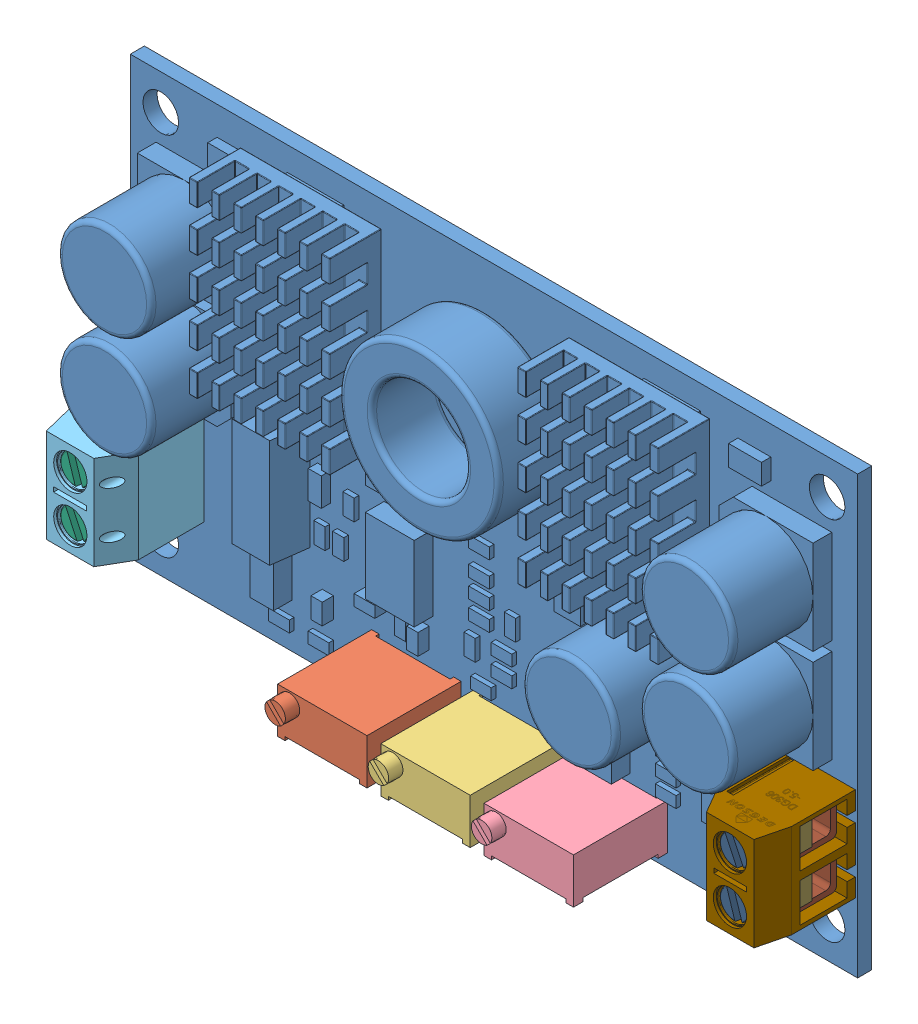
SolidWorks assembly LTC 3780 Mudule v11, configuration Predeterminado. Lengths in mm.
Overall size (77.5 46.5 15.68).
20 component instances, 12 part files, 0 mates.
Components (placement in the parent):
- LTC 3780 Mudule-1: LTC 3780 Mudule [Predeterminado] at origin size (77.5 46.5 14)
- Trimpot_3296W v1-1: Trimpot_3296W v1 [Predeterminado] at (-8.265 -19.415 0) x (-1 0 0) z (0 0 1) size (9.53 4.83 14.15)
- Trimpot_3296W v1 (1)-1: Trimpot_3296W v1 (1) [Predeterminado] at (2.735 -19.415 0) x (-1 0 0) z (0 0 1) size (9.53 4.83 14.15)
- Trimpot_3296W v1 (2)-1: Trimpot_3296W v1 (2) [Predeterminado] at (13.735 -19.415 0) x (-1 0 0) z (0 0 1) size (9.53 4.83 14.15)
- DG306-5 v2-1: DG306-5 v2 [Predeterminado] at (0 0 17) size (7.6 10.62 14.13)
  - Case-1: Case [Predeterminado] at (-38.5 -6 -17) x (0 -1 0) z (-1 0 0) size (10.62 10 7.6)
  - Screw-1: Screw [Predeterminado] at (-35.14 -8.5 -13.12) x (0.304322 -0.952569 0) z (-0.952569 -0.304322 0) size (3.38 5.66 3.38)
  - Terminal-1: Terminal [Predeterminado] at (-32.9 -6.55 -16.126) x (0 -1 0) z (-1 0 0) size (3.9 9.8 4.48)
  - Spring-1: Spring [Predeterminado] at (-37.5 -7.135 -13.226) x (0 -1 0) z (-1 0 0) size (2.73 2.2 5.76)
  - Screw-2: Screw [Predeterminado] at (-35.14 -13.5 -13.12) x (0.425528 -0.904945 0) z (-0.904945 -0.425528 0) size (3.38 5.66 3.38)
  - Terminal-2: Terminal [Predeterminado] at (-32.9 -11.55 -16.126) x (0 -1 0) z (-1 0 0) size (3.9 9.8 4.48)
  - Spring-2: Spring [Predeterminado] at (-37.5 -12.135 -13.226) x (0 -1 0) z (-1 0 0) size (2.73 2.2 5.76)
- DG306-5 v2 (1)-1: DG306-5 v2 (1) [Predeterminado] at origin size (7.6 10.62 14.13)
  - Case (1)-1: Case (1) [Predeterminado] at (38.5 -16 0) x (0 1 0) z (1 0 0) size (10.62 10 7.6)
  - Screw (1)-1: Screw (1) [Predeterminado] at (35.14 -13.5 3.88) x (-0.304322 0.952569 0) z (0.952569 0.304322 0) size (3.38 5.66 3.38)
  - Terminal (1)-1: Terminal (1) [Predeterminado] at (32.9 -15.45 0.874) x (0 1 0) z (1 0 0) size (3.9 9.8 4.48)
  - Spring (1)-1: Spring (1) [Predeterminado] at (37.5 -14.865 3.774) x (0 1 0) z (1 0 0) size (2.73 2.2 5.76)
  - Screw (1)-2: Screw (1) [Predeterminado] at (35.14 -8.5 3.88) x (-0.425528 0.904945 0) z (0.904945 0.425528 0) size (3.38 5.66 3.38)
  - Terminal (1)-2: Terminal (1) [Predeterminado] at (32.9 -10.45 0.874) x (0 1 0) z (1 0 0) size (3.9 9.8 4.48)
  - Spring (1)-2: Spring (1) [Predeterminado] at (37.5 -9.865 3.774) x (0 1 0) z (1 0 0) size (2.73 2.2 5.76)
